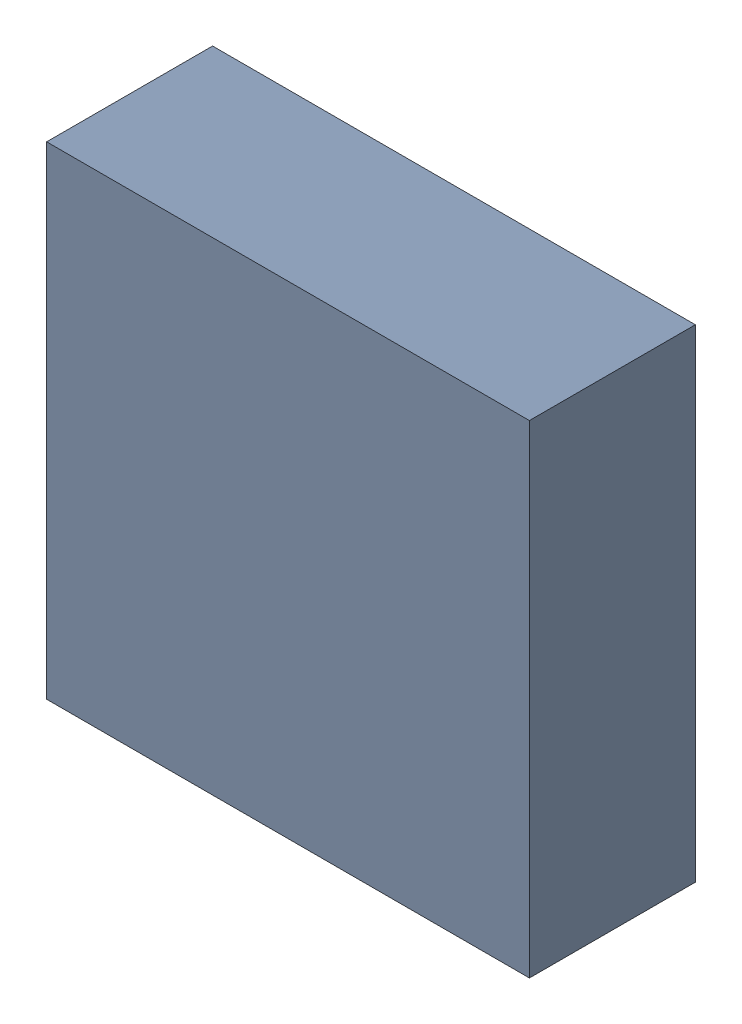
SolidWorks assembly U304_1PCB, configuration Default. Lengths in mm.
Overall size (3.2 3.2 1.1).
2 component instances, 1 part files, 0 mates.
Components (placement in the parent):
- 846484240-1: 846484240 [Default] at (132.4 110.5 0) size (3.2 3.2 1.1)
  - Extruded_11-1: Extruded_11 [Default] at origin size (3.2 3.2 1.1)
